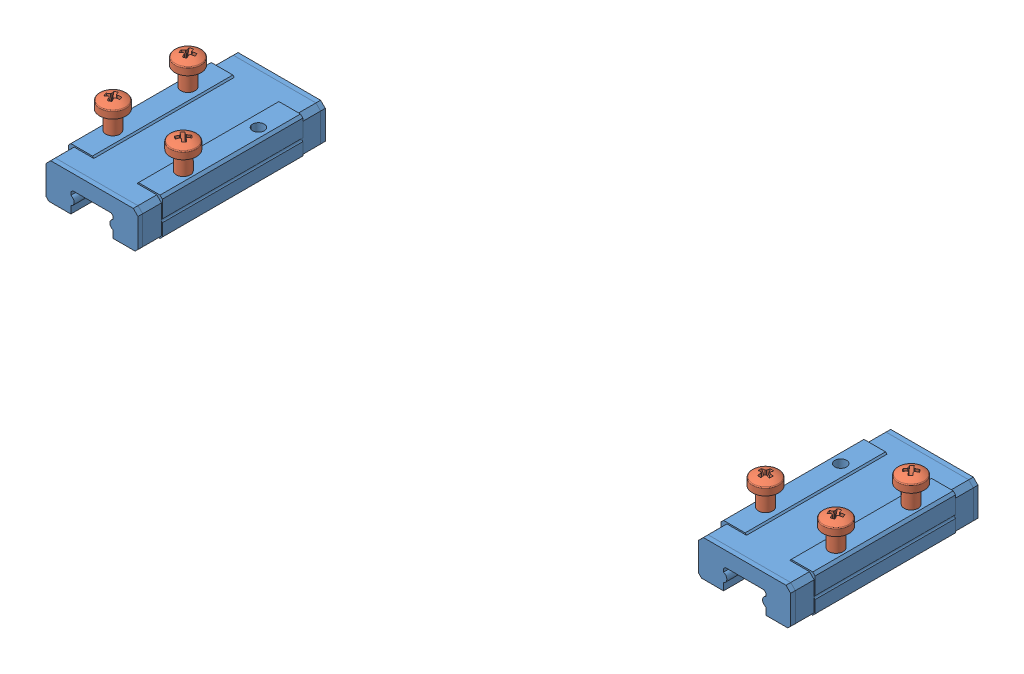
SolidWorks assembly Rail Assembly, configuration Default. Lengths in mm.
Overall size (161.6 14.41 39.97).
8 component instances, 2 part files, 4 mates.
Components (placement in the parent):
- Rail MGN9-1: Rail MGN9 [Default] at origin size (20 8.06 39.97)
- Rail MGN9-2: Rail MGN9 [Default] at (139 0 0) size (20 8.06 39.97)
- pan head cross recess screw_iso-1: pan head cross recess screw_iso [ISO 7045 - M3 x 6 - Z --- 6N] at (7.5 9.9 8) x (0 -1 0) z (-0.780168 0 -0.62557) size (8.35 5.6 5.6)
- pan head cross recess screw_iso-2: pan head cross recess screw_iso [ISO 7045 - M3 x 6 - Z --- 6N] at (-7.5 9.9 -8) x (0 -1 0) z (0.381849 0 0.924225) size (8.35 5.6 5.6)
- pan head cross recess screw_iso-3: pan head cross recess screw_iso [ISO 7045 - M3 x 6 - Z --- 6N] at (146.5 9.9 8) x (0 -1 0) z (-0.364107 0 -0.931357) size (8.35 5.6 5.6)
- pan head cross recess screw_iso-4: pan head cross recess screw_iso [ISO 7045 - M3 x 6 - Z --- 6N] at (131.5 9.9 8) x (0 -1 0) z (0.06083 0 -0.998148) size (8.35 5.6 5.6)
- pan head cross recess screw_iso-5: pan head cross recess screw_iso [ISO 7045 - M3 x 6 - Z --- 6N] at (146.5 9.9 -8) x (0 -1 0) z (0.647519 0 0.762049) size (8.35 5.6 5.6)
- pan head cross recess screw_iso-6: pan head cross recess screw_iso [ISO 7045 - M3 x 6 - Z --- 6N] at (-7.5 9.9 8) x (0 -1 0) z (0.381849 0 0.924225) size (8.35 5.6 5.6)
Mates (geometry in assembly coordinates):
- Concêntrico68: concentric: cylinder of pan head cross recess screw_iso-5 through (146.5 35.3 -8) axis (0 1 0) radius 1.5; cylinder of Rail MGN9-2 through (146.5 3.5 -8) axis (0 -1 0) radius 1.25
- Concêntrico75: concentric: cylinder of pan head cross recess screw_iso-4 through (131.5 35.3 8) axis (0 1 0) radius 1.5; cylinder of Rail MGN9-2 through (131.5 3.5 8) axis (0 -1 0) radius 1.25
- Concentric4005684: concentric: cylinder of pan head cross recess screw_iso-6 through (-7.5 35.3 8) axis (0 1 0) radius 1.5; cylinder of Rail MGN9-1 through (-7.5 3.5 8) axis (0 -1 0) radius 1.25
- Concentric4005685: concentric: cylinder of Rail MGN9-1 through (-7.5 3.5 8) axis (0 -1 0) radius 1.25; cylinder of pan head cross recess screw_iso-6 through (-7.5 35.3 8) axis (0 1 0) radius 1.5
